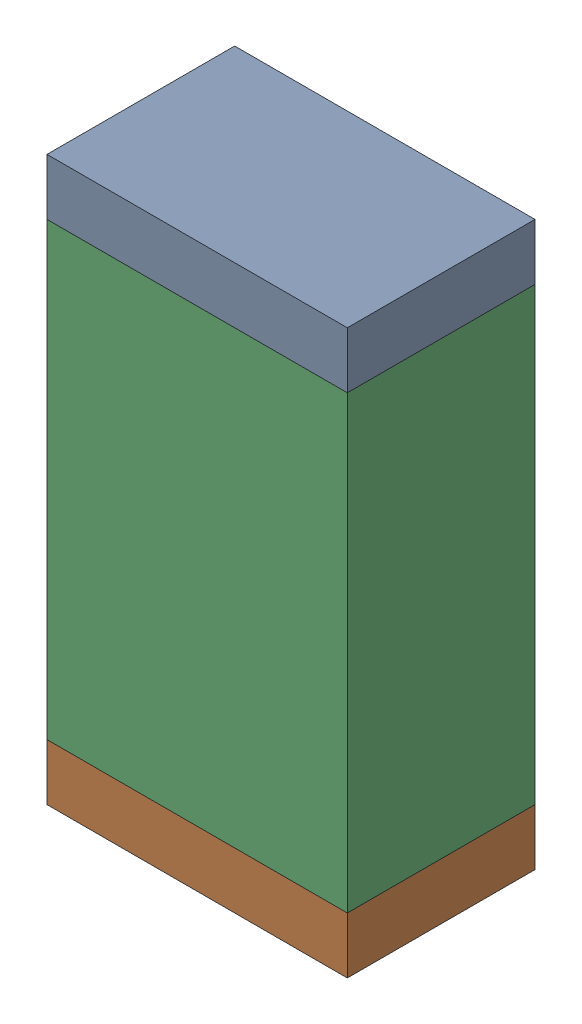
SolidWorks assembly R64, configuration Default. Lengths in mm.
Overall size (0.8 1.5 0.5).
6 component instances, 2 part files, 0 mates.
Components (placement in the parent):
- 810156592-1: 810156592 [Default] at (113.1 74.375 0) size (0.8 0.15 0.5)
  - Extruded_7-1: Extruded_7 [Default] at origin size (0.8 0.15 0.5)
- 810156592-2: 810156592 [Default] at (113.1 73.025 0) size (0.8 0.15 0.5)
  - Extruded_7-1: Extruded_7 [Default] at origin size (0.8 0.15 0.5)
- 810156976-1: 810156976 [Default] at (113.1 73.7 0) size (0.8 1.2 0.5)
  - Extruded_6-1: Extruded_6 [Default] at origin size (0.8 1.2 0.5)
